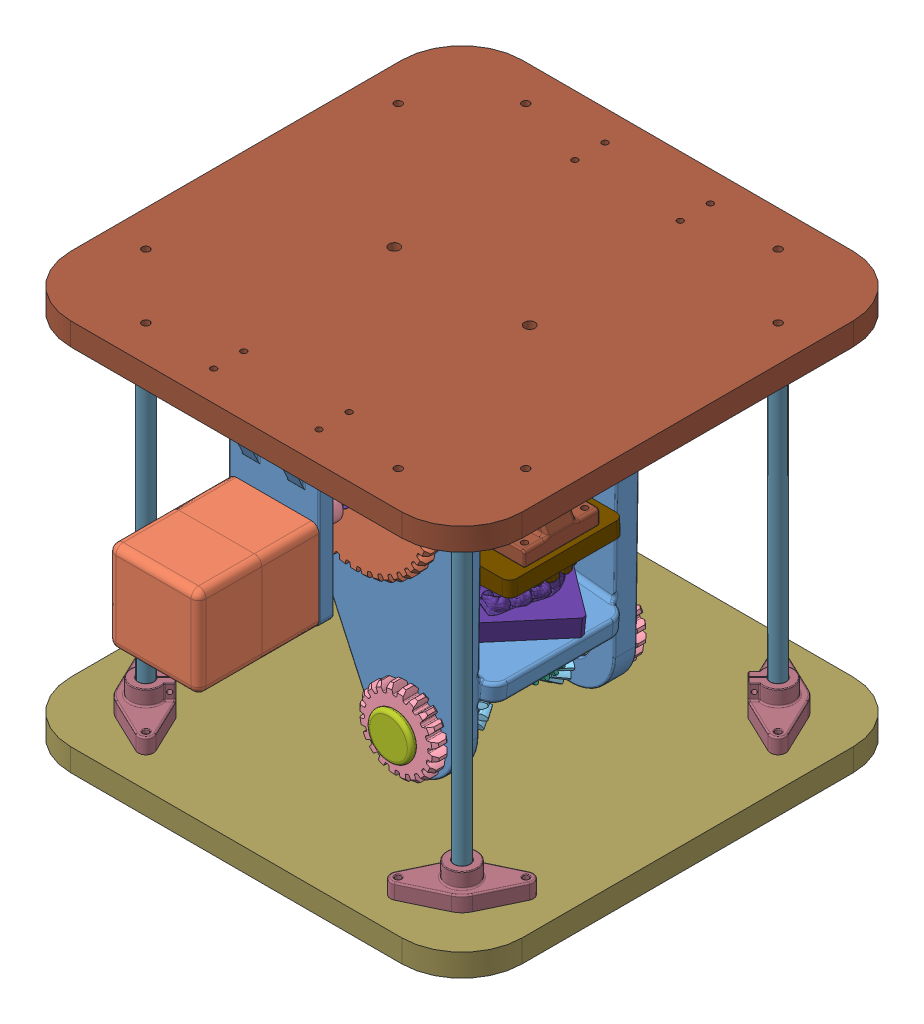
SolidWorks assembly ASSEMBLY Full Design 7th Attempt - New Design For Jaw, configuration Default. Lengths in mm.
Overall size (300 260 410).
50 component instances, 22 part files, 128 mates.
Components (placement in the parent):
- Main Case 02-1: Main Case 02 [Default] x (0.994892 -0.100948 0) z (0 0 1) size (133.56 212 120)
- Secondary Big Spur Gear-1: Secondary Big Spur Gear [Default] at (0 0 66) x (0.839597 -0.54321 0) z (0 0 1) size (100.6 100.6 10)
- Main Bearing-1: Main Bearing [Default] at (0 0 52.5) x (0.766521 -0.642219 0) z (0 0 1) size (25 25 10)
- Main Spur Gear - Copy-1: Main Spur Gear - Copy [Default] at (27.1772 -128.3994 66) x (-0.616536 0.787327 0) z (0 0 1) size (52.44 52.44 10)
- Main Bearing-2: Main Bearing [Default] at (27.1772 -128.3994 52.5) x (0.852233 -0.523163 0) z (0 0 1) size (25 25 10)
- Secondary Bevel Gear-1: Secondary Bevel Gear [Default] at (27.1772 -128.3994 29.8779) x (-0.616536 0.787327 0) z (-0.787327 -0.616536 0) size (38.4 11.9 38.26)
- Secondary Main Bevel Gear-1: Secondary Main Bevel Gear [Default] at (28.9257 -111.1673 0) x (0.807518 -0.081936 0.584125) z (0.581141 -0.058966 -0.811664) size (61.9 10.12 62)
- Secondary Big Spur Gear-2: Secondary Big Spur Gear [Default] at (0 0 -66) x (-0.772467 -0.635055 0) z (0 0 1) size (100.6 100.6 10)
- Main Spur Gear - Copy-2: Main Spur Gear - Copy [Default] at (27.1772 -128.3994 -66) x (0.568843 0.822446 0) z (0 0 1) size (52.44 52.44 10)
- Secondary Bevel Gear-2: Secondary Bevel Gear [Default] at (27.1772 -128.3994 -29.8779) x (-0.568843 -0.822446 0) z (-0.822446 0.568843 0) size (38.4 11.9 38.26)
- Main Bearing-3: Main Bearing [Default] at (0 0 -55) x (0.693553 -0.720406 0) z (0 0 1) size (25 25 10)
- Main Bearing-4: Main Bearing [Default] at (27.1772 -128.3994 -52.5) x (0.998806 0.048845 0) z (0 0 1) size (25 25 10)
- Gear Shaft - Lower-1: Gear Shaft - Lower [Default] at (27.1772 -128.3994 -71) x (0.568843 0.822446 0) z (0.822446 -0.568843 0) size (30 53 30)
- Gear Shaft - Lower-2: Gear Shaft - Lower [Default] at (27.1772 -128.3994 71) x (0.616536 -0.787327 0) z (0.787327 0.616536 0) size (30 53 30)
- Shaft Lock-1: Shaft Lock [Default] at (27.1772 -128.3994 -47.5) x (0.762116 0.64744 0) z (0.64744 -0.762116 0) size (20 10 20)
- Shaft Lock-2: Shaft Lock [Default] at (27.1772 -128.3994 47.5) x (-0.661226 0.750187 0) z (-0.750187 -0.661226 0) size (20 10 20)
- Main Rod-1: Main Rod [Default] at origin size (10 10 70)
- Rod Cap-1: Rod Cap [Default] at (0 0 -35) x (-0.994892 0.100948 0) z (0 0 1) size (44.95 22.5 20)
- Rod Cap-2: Rod Cap [Default] at (0 0 35) x (-0.994892 0.100948 0) z (0 0 1) size (44.95 22.5 20)
- Top Bracket-1: Top Bracket [Default] at (0 72.5 0) size (300 116.9 300)
- Main Bearing-5: Main Bearing [Default] at (0 0 18) size (25 25 10)
- Main Bearing-6: Main Bearing [Default] at (0 0 -18) size (25 25 10)
- Bottom Bracket-1: Bottom Bracket [Default] at (0 -180 0) size (300 15 300)
- Plate Docker-1: Plate Docker [Default] at (105 -165 -105) x (0.707107 0 0.707107) z (-0.707107 0 0.707107) size (70 20.03 29.14)
- Plate Docker-2: Plate Docker [Default] at (105 65 105) x (0.707107 0 -0.707107) z (-0.707107 0 -0.707107) size (70 20.03 29.14)
- Plate Docker-3: Plate Docker [Default] at (-105 65 -105) x (-0.707107 0 0.707107) z (0.707107 0 0.707107) size (70 20.03 29.14)
- Plate Docker-4: Plate Docker [Default] at (-105 -165 105) x (-0.707107 0 -0.707107) z (0.707107 0 -0.707107) size (70 20.03 29.14)
- Plate Docker-5: Plate Docker [Default] at (-105 -165 -105) x (0.707107 0 -0.707107) z (0.707107 0 0.707107) size (70 20.03 29.14)
- Plate Docker-6: Plate Docker [Default] at (-105 65 105) x (0.707107 0 0.707107) z (0.707107 0 -0.707107) size (70 20.03 29.14)
- Plate Docker-7: Plate Docker [Default] at (105 65 -105) x (-0.707107 0 -0.707107) z (-0.707107 0 0.707107) size (70 20.03 29.14)
- Plate Docker-8: Plate Docker [Default] at (105 -165 105) x (-0.707107 0 0.707107) z (-0.707107 0 -0.707107) size (70 20.03 29.14)
- Bracket Shaft-1: Bracket Shaft [Default] at (-105 -165 105) size (10 230 10)
- Bracket Shaft-2: Bracket Shaft [Default] at (-105 -165 -105) size (10 230 10)
- Bracket Shaft-3: Bracket Shaft [Default] at (105 -165 105) size (10 230 10)
- Bracket Shaft-4: Bracket Shaft [Default] at (105 -165 -105) size (10 230 10)
- Main Bearing-7: Main Bearing [Default] at (30.2056 -98.5526 0) x (0.994892 -0.100948 0) z (-0.100948 -0.994892 0) size (25 25 10)
- Vertical Bevel Shaft-1: Vertical Bevel Shaft [Default] at (28.7018 -113.3737 0) x (-0.807518 0.081936 -0.584125) z (0.581141 -0.058966 -0.811664) size (10 30 10)
- Jaw Install Plate-1: Jaw Install Plate [Default] at (30.7207 -93.4759 0) x (-0.807518 0.081936 -0.584125) z (0.581141 -0.058966 -0.811664) size (50 15 50)
- Ham duoi V1-1: Ham duoi V1 [Default] at (33.3867 -67.2017 0) x (-0.807518 0.081936 -0.584125) z (-0.200328 -0.969538 0.140944) size (76.11 56.45 29.14)
- Ham tren V1-2: Ham tren V1 [Default] at (38.2293 -54.5924 0.5024) x (0 0 -1) z (-0.121869 -0.992546 0) size (76.11 57.29 25.91)
- Motor Mount Plate-1: Motor Mount Plate [Default] at (0 12.5 115) size (80 105 30)
- Motor Mount Plate-2: Motor Mount Plate [Default] at (0 12.5 -125) size (80 105 30)
- Motor-1: Motor [Default] at (-30.0013 -39.9987 163) size (60 60 99)
- Motor-2: Motor [Default] at (30.0013 -39.9987 -163) x (-1 0 0) z (0 0 -1) size (60 60 99)
- Big Motor Shaft-1: Big Motor Shaft [Default] at (0 0 -100) x (0.73445 0.678663 0) z (0.678663 -0.73445 0) size (10 50 10)
- Big Motor Shaft-2: Big Motor Shaft [Default] at (0 0 50) x (0.969145 0.246493 0) z (0.246493 -0.969145 0) size (10 50 10)
- Motor Coupling-1: Motor Coupling [Default] at (0.0013 0.0013 -100.5) x (-1 0 0) z (0 0 -1) size (20 20 25)
- Motor Coupling-2: Motor Coupling [Default] at (-0.0013 0.0013 100.5) size (20 20 25)
- Shaft Lock-3: Shaft Lock [Default] at (0 0 71) x (1 0 0) z (0 -1 0) size (20 10 20)
- Shaft Lock-4: Shaft Lock [Default] at (0 0 -71) x (-1 0 0) z (0 -1 0) size (20 10 20)
Mates (geometry in assembly coordinates):
- Coincident1: coincident aligned: plane of Main Case 02-1 through (0 0 0) normal (0 0 1)
- Concentric2: concentric aligned: cylinder of Main Case 02-1 through (0 0 45) axis (0 0 1) radius 12.5; cylinder of Secondary Big Spur Gear-1 through (0 0 61) axis (0 0 1) radius 5
- Distance1: distance = 1 mm anti-aligned: plane of Secondary Big Spur Gear-1 through (0 0 61) normal (0 0 -1); plane of Main Case 02-1 through (0 0 60) normal (0 0 1)
- Concentric3: concentric anti-aligned: cylinder of Main Case 02-1 through (0 0 45) axis (0 0 1) radius 12.5; cylinder of Main Bearing-1 through (0 0 57.5) axis (0 0 -1) radius 12.5
- Width1: width aligned: plane of Main Bearing-1 through (0 0 47.5) normal (0 0 -1); plane of Main Case 02-1 through (0 0 57.5) normal (0 0 1); plane of Main Bearing-1 through (0 0 45) normal (0 0 -1); plane of Main Case 02-1 through (0 0 60) normal (0 0 1)
- Concentric4: concentric aligned: cylinder of Main Case 02-1 through (27.1772 -128.3994 45) axis (0 0 1) radius 12.5; cylinder of Main Spur Gear - Copy-1 through (27.1772 -128.3994 61) axis (0 0 1) radius 5
- Concentric5: concentric anti-aligned: cylinder of Main Case 02-1 through (27.1772 -128.3994 45) axis (0 0 1) radius 12.5; cylinder of Main Bearing-2 through (27.1772 -128.3994 57.5) axis (0 0 -1) radius 5
- Width2: width anti-aligned: plane of Main Bearing-2 through (27.1772 -128.3994 47.5) normal (0 0 -1); plane of Main Case 02-1 through (27.1772 -128.3994 57.5) normal (0 0 1); plane of Main Bearing-2 through (0 0 60) normal (0 0 1); plane of Main Case 02-1 through (0 0 45) normal (0 0 -1)
- Concentric6: concentric aligned: cylinder of Main Case 02-1 through (27.1772 -128.3994 45) axis (0 0 1) radius 12.5; cylinder of Secondary Bevel Gear-1 through (27.1772 -128.3994 20.4194) axis (0 0 1) radius 5
- Coincident5: coincident aligned: plane of Main Spur Gear - Copy-1 through (24.8023 -132.7994 61) normal (-0.616536 0.787327 0); plane of Secondary Bevel Gear-1 through (24.8023 -132.7994 20.4194) normal (-0.616536 0.787327 0)
- Concentric7: concentric aligned: cylinder of Main Case 02-1 through (29.7009 -103.5271 0) axis (0.100948 0.994892 0) radius 12.5; cylinder of Secondary Main Bevel Gear-1 through (28.2973 -117.3601 0) axis (0.100948 0.994892 0) radius 5
- Coincident6: coincident: point of Secondary Bevel Gear-1; point of Secondary Main Bevel Gear-1
- GearMate1: gear = 60 : 34.5 mm: circle of Secondary Bevel Gear-1; circle of Secondary Main Bevel Gear-1
- GearMate2: gear = 96 : 48 mm: circle of Main Spur Gear - Copy-1; circle of Secondary Big Spur Gear-1
- Concentric10: concentric anti-aligned: cylinder of Main Case 02-1 through (27.1772 -128.3994 -45) axis (0 0 -1) radius 12.5; cylinder of Main Spur Gear - Copy-2 through (27.1772 -128.3994 -71) axis (0 0 1) radius 5
- Distance3: distance = 1 mm anti-aligned: plane of Main Spur Gear - Copy-2 through (27.1772 -128.3994 -61) normal (0 0 1); plane of Main Case 02-1 through (0 0 -60) normal (0 0 -1)
- Concentric11: concentric anti-aligned: cylinder of Main Case 02-1 through (0 0 -45) axis (0 0 -1) radius 12.5; cylinder of Secondary Big Spur Gear-2 through (0 0 -71) axis (0 0 1) radius 5
- Distance4: distance = 1 mm anti-aligned: plane of Secondary Big Spur Gear-2 through (0 0 -61) normal (0 0 1); plane of Main Case 02-1 through (0 0 -60) normal (0 0 -1)
- Concentric12: concentric anti-aligned: cylinder of Main Spur Gear - Copy-2 through (27.1772 -128.3994 -71) axis (0 0 1) radius 5; cylinder of Secondary Bevel Gear-2 through (27.1772 -128.3994 -20.4194) axis (0 0 -1) radius 5
- Coincident9: coincident: point of Secondary Bevel Gear-1; point of Secondary Bevel Gear-2
- GearMate3: gear = 34.5 : 60 mm: circle of Secondary Main Bevel Gear-1; circle of Secondary Bevel Gear-2
- GearMate4: gear = 96 : 48 mm: circle of Main Spur Gear - Copy-2; circle of Secondary Big Spur Gear-2
- Coincident10: coincident aligned: plane of Main Spur Gear - Copy-2 through (24.546 -124.1477 -71) normal (-0.568843 -0.822446 0); plane of Secondary Bevel Gear-2 through (24.546 -124.1477 -20.4194) normal (-0.568843 -0.822446 0)
- Concentric14: concentric aligned: cylinder of Main Case 02-1 through (27.1772 -128.3994 -45) axis (0 0 -1) radius 12.5; cylinder of Main Bearing-4 through (27.1772 -128.3994 -47.5) axis (0 0 -1) radius 12.5
- Width3: width anti-aligned: plane of Main Bearing-4 through (27.1772 -128.3994 -57.5) normal (0 0 -1); plane of Main Case 02-1 through (27.1772 -128.3994 -47.5) normal (0 0 1); plane of Main Bearing-4 through (0 0 -45) normal (0 0 1); plane of Main Case 02-1 through (0 0 -60) normal (0 0 -1)
- Concentric15: concentric aligned: cylinder of Main Case 02-1 through (0 0 -45) axis (0 0 -1) radius 12.5; cylinder of Main Bearing-3 through (0 0 -50) axis (0 0 -1) radius 5
- Concentric16: concentric anti-aligned: cylinder of Main Spur Gear - Copy-2 through (27.1772 -128.3994 -71) axis (0 0 1) radius 5; cylinder of Gear Shaft - Lower-1 through (27.1772 -128.3994 -23) axis (0 0 -1) radius 5
- Coincident11: coincident anti-aligned: plane of Main Spur Gear - Copy-2 through (27.1772 -128.3994 -71) normal (0 0 -1); plane of Gear Shaft - Lower-1 through (27.1772 -128.3994 -71) normal (0 0 1)
- Parallel1: parallel anti-aligned: plane of Secondary Bevel Gear-2 through (22.5578 -122.7726 -20.4194) normal (0.822446 -0.568843 0); plane of Gear Shaft - Lower-1 through (23.5722 -128.3377 -33) normal (-0.822446 0.568843 0)
- Concentric17: concentric aligned: cylinder of Main Spur Gear - Copy-1 through (27.1772 -128.3994 61) axis (0 0 1) radius 5; cylinder of Gear Shaft - Lower-2 through (27.1772 -128.3994 23) axis (0 0 1) radius 5
- Coincident13: coincident anti-aligned: plane of Main Spur Gear - Copy-1 through (27.1772 -128.3994 71) normal (0 0 1); plane of Gear Shaft - Lower-2 through (27.1772 -128.3994 71) normal (0 0 -1)
- Coincident14: coincident aligned: plane of Secondary Bevel Gear-1 through (22.3361 -129.65 20.4194) normal (0.616536 -0.787327 0); plane of Gear Shaft - Lower-2 through (23.5821 -128.6743 33) normal (0.616536 -0.787327 0)
- Concentric18: concentric aligned: cylinder of Gear Shaft - Lower-1 through (27.1772 -128.3994 -23) axis (0 0 -1) radius 5; cylinder of Shaft Lock-1 through (27.1772 -128.3994 -44.5) axis (0 0 -1) radius 5
- Coincident15: coincident anti-aligned: plane of Main Bearing-4 through (27.1772 -128.3994 -47.5) normal (0 0 1); plane of Shaft Lock-1 through (27.1772 -128.3994 -47.5) normal (0 0 -1)
- Concentric19: concentric aligned: cylinder of Gear Shaft - Lower-2 through (27.1772 -128.3994 23) axis (0 0 1) radius 5; cylinder of Shaft Lock-2 through (27.1772 -128.3994 37.5) axis (0 0 1) radius 7
- Coincident16: coincident anti-aligned: plane of Main Bearing-2 through (27.1772 -128.3994 47.5) normal (0 0 -1); plane of Shaft Lock-2 through (27.1772 -128.3994 47.5) normal (0 0 1)
- Distance5: distance = 1 mm anti-aligned: plane of Main Spur Gear - Copy-1 through (27.1772 -128.3994 61) normal (0 0 -1); plane of Main Case 02-1 through (0 0 60) normal (0 0 1)
- Coincident19: coincident: point of Main Case 02-1; point of assembly
- Coincident20: coincident aligned: plane of Main Case 02-1 through (0 0 -60) normal (0 0 -1); plane of Main Bearing-3 through (0 0 -60) normal (0 0 -1)
- Concentric20: concentric aligned: cylinder of Main Case 02-1 through (0 0 35) axis (0 0 -1) radius 5; cylinder of Main Rod-1 through (0 0 35) axis (0 0 -1) radius 5
- Coincident21: coincident anti-aligned: plane of Main Case 02-1 through (0 0 -35) normal (0 0 1); plane of Main Rod-1 through (0 0 -35) normal (0 0 -1)
- Coincident22: coincident anti-aligned: plane of Main Case 02-1 through (-22.3851 2.2713 -25) normal (0.100948 0.994892 0); plane of Rod Cap-1 through (22.3851 -2.2713 -25) normal (-0.100948 -0.994892 0)
- Concentric21: concentric anti-aligned: cylinder of Main Case 02-1 through (11.6608 -21.2859 -35) axis (0.100948 0.994892 0) radius 2; cylinder of Rod Cap-1 through (15.9511 20.997 -35) axis (-0.100948 -0.994892 0) radius 2
- Concentric22: concentric anti-aligned: cylinder of Main Case 02-1 through (-15.6987 -18.5098 -35) axis (0.100948 0.994892 0) radius 2; cylinder of Rod Cap-1 through (-11.4084 23.7731 -35) axis (-0.100948 -0.994892 0) radius 2
- Concentric23: concentric anti-aligned: cylinder of Main Case 02-1 through (11.6608 -21.2859 35) axis (0.100948 0.994892 0) radius 2; cylinder of Rod Cap-2 through (15.9511 20.997 35) axis (-0.100948 -0.994892 0) radius 2
- Coincident23: coincident anti-aligned: plane of Main Case 02-1 through (-22.3851 2.2713 25) normal (0.100948 0.994892 0); plane of Rod Cap-2 through (22.3851 -2.2713 45) normal (-0.100948 -0.994892 0)
- Concentric24: concentric anti-aligned: cylinder of Main Case 02-1 through (-15.6987 -18.5098 35) axis (0.100948 0.994892 0) radius 2; cylinder of Rod Cap-2 through (-11.4084 23.7731 35) axis (-0.100948 -0.994892 0) radius 2
- Concentric26: concentric anti-aligned: cylinder of Main Rod-1 through (0 0 35) axis (0 0 -1) radius 5; cylinder of Top Bracket-1 through (0 0 13) axis (0 0 1) radius 10
- Width4: width anti-aligned: plane of Main Case 02-1 through (0 0 -45) normal (0 0 1); plane of Main Case 02-1 through (0 0 45) normal (0 0 -1); plane of Top Bracket-1 through (0 0 -23) normal (0 0 -1); plane of Top Bracket-1 through (0 0 23) normal (0 0 1)
- Parallel9: parallel anti-aligned: plane of Top Bracket-1 through (-150 65 150) normal (0 -1 0)
- Coincident33: coincident aligned: plane of Top Bracket-1 through (0 0 -23) normal (0 0 -1); plane of Main Bearing-6 through (0 0 -23) normal (0 0 -1)
- Concentric28: concentric aligned: cylinder of Main Rod-1 through (0 0 35) axis (0 0 -1) radius 5; cylinder of Main Bearing-6 through (0 0 -13) axis (0 0 -1) radius 5
- Coincident34: coincident aligned: plane of Top Bracket-1 through (0 0 23) normal (0 0 1); plane of Main Bearing-5 through (0 0 23) normal (0 0 1)
- Concentric29: concentric aligned: cylinder of Main Rod-1 through (0 0 35) axis (0 0 -1) radius 5; cylinder of Main Bearing-5 through (0 0 23) axis (0 0 -1) radius 5
- Coincident35: coincident aligned: plane of Top Bracket-1 through (0 72.5 0) normal (0 0 1); plane of Bottom Bracket-1 through (0 -180 0) normal (0 0 1)
- Coincident36: coincident aligned: plane of Top Bracket-1 through (0 72.5 0) normal (1 0 0); plane of Bottom Bracket-1 through (0 -180 0) normal (1 0 0)
- Distance6: distance = 230 mm anti-aligned: plane of Bottom Bracket-1 through (0 -165 0) normal (0 1 0); plane of Top Bracket-1 through (-150 65 150) normal (0 -1 0)
- Concentric30: concentric anti-aligned: circle of Bottom Bracket-1; cylinder of Plate Docker-1 through (105 -155 -105) axis (0 -1 0) radius 5
- Coincident37: coincident anti-aligned: plane of Bottom Bracket-1 through (0 -165 0) normal (0 1 0); plane of Plate Docker-1 through (83.7868 -165 -126.2132) normal (0 -1 0)
- Concentric31: concentric aligned: cylinder of Bottom Bracket-1 through (126.2132 -180 -83.7868) axis (0 1 0) radius 2.5; cylinder of Plate Docker-1 through (126.2132 -165 -83.7868) axis (0 1 0) radius 2
- Concentric32: concentric aligned: cylinder of Bottom Bracket-1 through (-126.2132 -180 -83.7868) axis (0 1 0) radius 2.5; cylinder of Plate Docker-5 through (-126.2132 -165 -83.7868) axis (0 1 0) radius 2
- Coincident38: coincident anti-aligned: plane of Bottom Bracket-1 through (0 -165 0) normal (0 1 0); plane of Plate Docker-5 through (-126.2132 -165 -83.7868) normal (0 -1 0)
- Concentric33: concentric aligned: cylinder of Bottom Bracket-1 through (-83.7868 -180 -126.2132) axis (0 1 0) radius 2.5; cylinder of Plate Docker-5 through (-83.7868 -165 -126.2132) axis (0 1 0) radius 2
- Coincident39: coincident anti-aligned: plane of Bottom Bracket-1 through (0 -165 0) normal (0 1 0); plane of Plate Docker-8 through (126.2132 -165 83.7868) normal (0 -1 0)
- Concentric35: concentric aligned: cylinder of Bottom Bracket-1 through (83.7868 -180 126.2132) axis (0 1 0) radius 2.5; cylinder of Plate Docker-8 through (83.7868 -165 126.2132) axis (0 1 0) radius 2
- Concentric36: concentric aligned: cylinder of Bottom Bracket-1 through (126.2132 -180 83.7868) axis (0 1 0) radius 2.5; cylinder of Plate Docker-8 through (126.2132 -165 83.7868) axis (0 1 0) radius 2
- Coincident40: coincident anti-aligned: plane of Bottom Bracket-1 through (0 -165 0) normal (0 1 0); plane of Plate Docker-4 through (-83.7868 -165 126.2132) normal (0 -1 0)
- Concentric37: concentric aligned: cylinder of Bottom Bracket-1 through (-126.2132 -180 83.7868) axis (0 1 0) radius 2.5; cylinder of Plate Docker-4 through (-126.2132 -165 83.7868) axis (0 1 0) radius 2
- Concentric38: concentric aligned: cylinder of Bottom Bracket-1 through (-83.7868 -180 126.2132) axis (0 1 0) radius 2.5; cylinder of Plate Docker-4 through (-83.7868 -165 126.2132) axis (0 1 0) radius 2
- Coincident42: coincident anti-aligned: plane of Top Bracket-1 through (-150 65 150) normal (0 -1 0); plane of Plate Docker-2 through (83.7868 65 126.2132) normal (0 1 0)
- Concentric40: concentric aligned: cylinder of Top Bracket-1 through (83.7868 80 126.2132) axis (0 -1 0) radius 2.5; cylinder of Plate Docker-2 through (83.7868 65 126.2132) axis (0 -1 0) radius 2
- Concentric41: concentric aligned: cylinder of Top Bracket-1 through (126.2132 80 83.7868) axis (0 -1 0) radius 2.5; cylinder of Plate Docker-2 through (126.2132 65 83.7868) axis (0 -1 0) radius 2
- Coincident43: coincident anti-aligned: plane of Top Bracket-1 through (-150 65 150) normal (0 -1 0); plane of Plate Docker-6 through (-126.2132 65 83.7868) normal (0 1 0)
- Concentric42: concentric aligned: cylinder of Top Bracket-1 through (-83.7868 80 126.2132) axis (0 -1 0) radius 2.5; cylinder of Plate Docker-6 through (-83.7868 65 126.2132) axis (0 -1 0) radius 2
- Concentric43: concentric aligned: cylinder of Top Bracket-1 through (-126.2132 80 83.7868) axis (0 -1 0) radius 2.5; cylinder of Plate Docker-6 through (-126.2132 65 83.7868) axis (0 -1 0) radius 2
- Coincident44: coincident anti-aligned: plane of Top Bracket-1 through (-150 65 150) normal (0 -1 0); plane of Plate Docker-3 through (-83.7868 65 -126.2132) normal (0 1 0)
- Concentric45: concentric aligned: cylinder of Top Bracket-1 through (-83.7868 80 -126.2132) axis (0 -1 0) radius 2.5; cylinder of Plate Docker-3 through (-83.7868 65 -126.2132) axis (0 -1 0) radius 2
- Concentric46: concentric aligned: cylinder of Top Bracket-1 through (-126.2132 80 -83.7868) axis (0 -1 0) radius 2.5; cylinder of Plate Docker-3 through (-126.2132 65 -83.7868) axis (0 -1 0) radius 2
- Coincident45: coincident anti-aligned: plane of Top Bracket-1 through (-150 65 150) normal (0 -1 0); plane of Plate Docker-7 through (126.2132 65 -83.7868) normal (0 1 0)
- Concentric47: concentric aligned: cylinder of Top Bracket-1 through (83.7868 80 -126.2132) axis (0 -1 0) radius 2.5; cylinder of Plate Docker-7 through (83.7868 65 -126.2132) axis (0 -1 0) radius 2
- Concentric48: concentric aligned: cylinder of Top Bracket-1 through (126.2132 80 -83.7868) axis (0 -1 0) radius 2.5; cylinder of Plate Docker-7 through (126.2132 65 -83.7868) axis (0 -1 0) radius 2
- Concentric49: concentric aligned: cylinder of Plate Docker-4 through (-105 -155 105) axis (0 -1 0) radius 5; cylinder of Bracket Shaft-1 through (-105 65 105) axis (0 -1 0) radius 5
- Coincident46: coincident anti-aligned: plane of Top Bracket-1 through (-150 65 150) normal (0 -1 0); plane of Bracket Shaft-1 through (-105 65 105) normal (0 1 0)
- Concentric50: concentric anti-aligned: cylinder of Plate Docker-7 through (105 55 -105) axis (0 1 0) radius 5; cylinder of Bracket Shaft-4 through (105 65 -105) axis (0 -1 0) radius 5
- Coincident47: coincident anti-aligned: plane of Top Bracket-1 through (-150 65 150) normal (0 -1 0); plane of Bracket Shaft-4 through (105 65 -105) normal (0 1 0)
- Concentric51: concentric anti-aligned: cylinder of Plate Docker-2 through (105 45 105) axis (0 1 0) radius 10; cylinder of Bracket Shaft-3 through (105 65 105) axis (0 -1 0) radius 5
- Coincident48: coincident anti-aligned: plane of Top Bracket-1 through (-150 65 150) normal (0 -1 0); plane of Bracket Shaft-3 through (105 65 105) normal (0 1 0)
- Concentric52: concentric aligned: cylinder of Plate Docker-5 through (-105 -155 -105) axis (0 -1 0) radius 5; cylinder of Bracket Shaft-2 through (-105 65 -105) axis (0 -1 0) radius 5
- Coincident49: coincident anti-aligned: plane of Top Bracket-1 through (-150 65 150) normal (0 -1 0); plane of Bracket Shaft-2 through (-105 65 -105) normal (0 1 0)
- Concentric53: concentric aligned: cylinder of Main Case 02-1 through (29.7009 -103.5271 0) axis (0.100948 0.994892 0) radius 12.5; cylinder of Main Bearing-7 through (29.7009 -103.5271 0) axis (0.100948 0.994892 0) radius 12.5
- Coincident50: coincident aligned: plane of Main Case 02-1 through (65.5316 -97.1113 -71.0211) normal (0.100948 0.994892 0); plane of Main Bearing-7 through (30.7104 -93.5782 0) normal (0.100948 0.994892 0)
- Concentric54: concentric anti-aligned: cylinder of Secondary Main Bevel Gear-1 through (28.2973 -117.3601 0) axis (0.100948 0.994892 0) radius 5; cylinder of Vertical Bevel Shaft-1 through (31.7302 -83.527 0) axis (-0.100948 -0.994892 0) radius 5
- Coincident52: coincident aligned: plane of Secondary Main Bevel Gear-1 through (12.7512 -111.7553 -11.538) normal (-0.100948 -0.994892 0); plane of Vertical Bevel Shaft-1 through (28.7018 -113.3737 0) normal (-0.100948 -0.994892 0)
- Coincident53: coincident aligned: plane of Secondary Main Bevel Gear-1 through (32.5755 -117.7942 -2.5513) normal (-0.807518 0.081936 -0.584125); plane of Vertical Bevel Shaft-1 through (33.0697 -103.7656 -1.2667) normal (-0.807518 0.081936 -0.584125)
- Coincident54: coincident anti-aligned: plane of Vertical Bevel Shaft-1 through (31.7302 -83.527 0) normal (0.100948 0.994892 0); plane of Jaw Install Plate-1 through (60.892 -86.4859 -4.7783) normal (-0.100948 -0.994892 0)
- Concentric55: concentric aligned: cylinder of Vertical Bevel Shaft-1 through (31.7302 -83.527 0) axis (-0.100948 -0.994892 0) radius 5; cylinder of Jaw Install Plate-1 through (31.7302 -83.527 0) axis (-0.100948 -0.994892 0) radius 10
- Coincident55: coincident aligned: plane of Vertical Bevel Shaft-1 through (28.7018 -113.3737 0) normal (0.581141 -0.058966 -0.811664); plane of Jaw Install Plate-1 through (30.7207 -93.4759 0) normal (0.581141 -0.058966 -0.811664)
- Coincident56: coincident anti-aligned: plane of Jaw Install Plate-1 through (61.3968 -81.5115 -4.7783) normal (0.100948 0.994892 0); plane of Ham duoi V1-1 through (32.235 -78.5525 0) normal (-0.100948 -0.994892 0)
- Concentric56: concentric aligned: cylinder of Jaw Install Plate-1 through (60.0081 -81.3705 -4.5508) axis (-0.100948 -0.994892 0) radius 2; cylinder of Ham duoi V1-1 through (60.6138 -75.4012 -4.5508) axis (-0.100948 -0.994892 0) radius 2
- Concentric58: concentric aligned: cylinder of Jaw Install Plate-1 through (27.7074 -78.0931 -27.9158) axis (-0.100948 -0.994892 0) radius 2; cylinder of Ham duoi V1-1 through (28.3131 -72.1238 -27.9158) axis (-0.100948 -0.994892 0) radius 2
- Coincident73: coincident anti-aligned: plane of Top Bracket-1 through (16.5 -36.9 25) normal (0 -1 0); plane of Ham tren V1-2 through (38.2293 -36.9 -94.448) normal (0 1 0)
- Concentric59: concentric aligned: cylinder of Top Bracket-1 through (61.5 -46.9 -20) axis (0 1 0) radius 2; cylinder of Ham tren V1-2 through (61.5 -44.9 -20) axis (0 1 0) radius 2
- Concentric60: concentric aligned: cylinder of Top Bracket-1 through (61.5 -46.9 20) axis (0 1 0) radius 2; cylinder of Ham tren V1-2 through (61.5 -44.9 20) axis (0 1 0) radius 2
- Coincident74: coincident anti-aligned: plane of Top Bracket-1 through (-150 65 150) normal (0 -1 0); plane of Motor Mount Plate-1 through (-30 65 125) normal (0 1 0)
- Coincident75: coincident anti-aligned: plane of Top Bracket-1 through (-150 65 150) normal (0 -1 0); plane of Motor Mount Plate-2 through (-30 65 -115) normal (0 1 0)
- Concentric61: concentric anti-aligned: cylinder of Top Bracket-1 through (-35 80 -130) axis (0 -1 0) radius 2; cylinder of Motor Mount Plate-2 through (-35 55 -130) axis (0 1 0) radius 2
- Concentric62: concentric anti-aligned: cylinder of Top Bracket-1 through (35 80 -110) axis (0 -1 0) radius 2; cylinder of Motor Mount Plate-2 through (35 55 -110) axis (0 1 0) radius 2
- Concentric63: concentric anti-aligned: cylinder of Top Bracket-1 through (35 80 130) axis (0 -1 0) radius 2; cylinder of Motor Mount Plate-1 through (35 55 130) axis (0 1 0) radius 2
- Concentric64: concentric anti-aligned: cylinder of Top Bracket-1 through (-35 80 110) axis (0 -1 0) radius 2; cylinder of Motor Mount Plate-1 through (-35 55 110) axis (0 1 0) radius 2
- Coincident76: coincident anti-aligned: plane of Motor Mount Plate-1 through (0 12.5 125) normal (0 0 1); plane of Motor-1 through (-30.0013 -39.9987 125) normal (0 0 -1)
- Tangent1: tangent aligned: cylinder of Motor-1 through (-24.75 14.75 135) axis (0 0 -1) radius 2.25; cylinder of Motor Mount Plate-1 through (-24.75 14.75 105) axis (0 0 1) radius 2.25
- Coincident78: coincident anti-aligned: plane of Motor Mount Plate-2 through (0 12.5 -125) normal (0 0 -1); plane of Motor-2 through (30.0013 -39.9987 -125) normal (0 0 1)
- Concentric71: concentric aligned: cylinder of Motor Mount Plate-2 through (24.75 14.75 -135) axis (0 0 1) radius 2.25; cylinder of Motor-2 through (24.75 14.75 -135) axis (0 0 1) radius 2.25
- Parallel28: parallel aligned: cylinder of Motor Mount Plate-2 through (-24.75 14.75 -135) axis (0 0 1) radius 2.25; cylinder of Motor-2 through (-24.7475 14.75 -135) axis (0 0 1) radius 2.25
- Parallel29: parallel aligned: plane of Motor Mount Plate-1 through (0 12.5 115) normal (1 0 0); plane of Motor-1 through (-30.0013 -39.9987 163) normal (1 0 0)
- Parallel30: parallel anti-aligned: plane of Motor Mount Plate-2 through (0 12.5 -125) normal (1 0 0); plane of Motor-2 through (30.0013 -39.9987 -163) normal (-1 0 0)
- Concentric75: concentric anti-aligned: cylinder of Secondary Big Spur Gear-1 through (0 0 61) axis (0 0 1) radius 5; cylinder of Big Motor Shaft-2 through (0 0 100) axis (0 0 -1) radius 5
- Coincident81: coincident anti-aligned: plane of Main Case 02-1 through (0 0 50) normal (0 0 1); plane of Big Motor Shaft-2 through (0 0 50) normal (0 0 -1)
- Concentric76: concentric anti-aligned: circle of Main Bearing-3; cylinder of Big Motor Shaft-1 through (0 0 -50) axis (0 0 -1) radius 5
- Coincident82: coincident anti-aligned: plane of Main Case 02-1 through (0 0 -50) normal (0 0 -1); plane of Big Motor Shaft-1 through (0 0 -50) normal (0 0 1)
- Distance9: distance = 7 mm anti-aligned: plane of Motor Coupling-1 through (0.0013 0.0013 -113) normal (0 0 -1); plane of Motor-2 through (0.0013 0.0013 -106) normal (0 0 1)
- Concentric77: concentric aligned: cylinder of Motor-2 through (0.0013 0.0013 -106) axis (0 0 -1) radius 2.5; cylinder of Motor Coupling-1 through (0.0013 0.0013 -105) axis (0 0 -1) radius 2.5
- Distance10: distance = 7 mm anti-aligned: plane of Motor Coupling-2 through (-0.0013 0.0013 113) normal (0 0 1); plane of Motor-1 through (-0.0013 0.0013 106) normal (0 0 -1)
- Concentric78: concentric anti-aligned: cylinder of Motor-1 through (-0.0013 0.0013 106) axis (0 0 1) radius 2.5; cylinder of Motor Coupling-2 through (-0.0013 0.0013 113) axis (0 0 -1) radius 10
- Concentric79: concentric aligned: cylinder of Big Motor Shaft-2 through (0 0 100) axis (0 0 -1) radius 5; cylinder of Shaft Lock-3 through (0 0 74) axis (0 0 -1) radius 5
- Coincident85: coincident anti-aligned: plane of Secondary Big Spur Gear-1 through (0 0 71) normal (0 0 1); plane of Shaft Lock-3 through (0 0 71) normal (0 0 -1)
- Concentric80: concentric anti-aligned: cylinder of Big Motor Shaft-1 through (0 0 -50) axis (0 0 -1) radius 5; cylinder of Shaft Lock-4 through (0 0 -74) axis (0 0 1) radius 5
- Coincident86: coincident anti-aligned: plane of Secondary Big Spur Gear-2 through (0 0 -71) normal (0 0 -1); plane of Shaft Lock-4 through (0 0 -71) normal (0 0 1)
